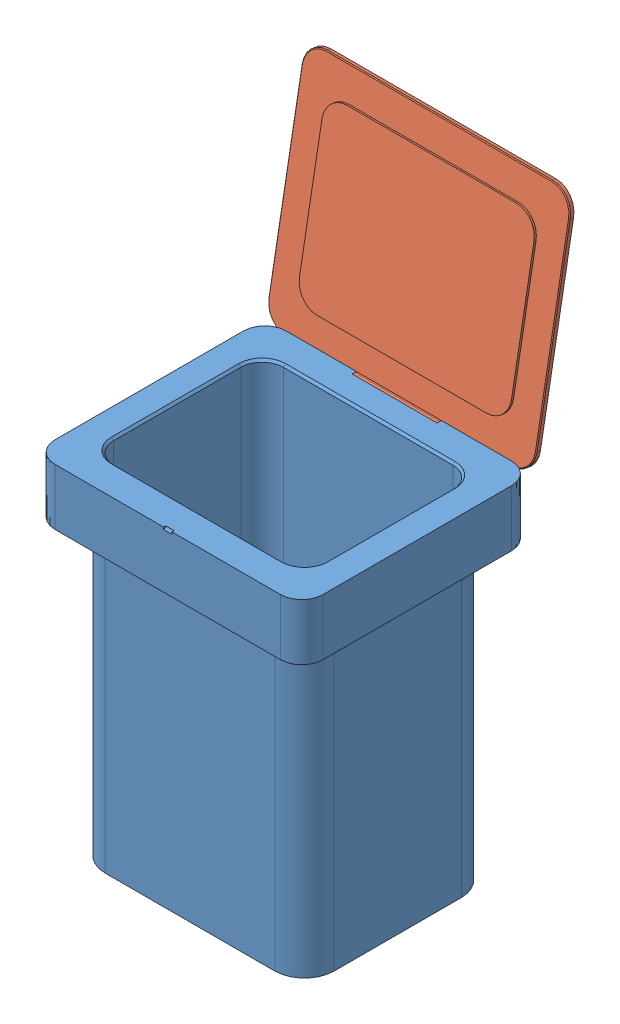
SolidWorks assembly Bin_assembly, configuration Default. Lengths in mm.
Overall size (632 1355.43 649.91).
2 component instances, 2 part files, 2 mates.
Components (placement in the parent):
- bin_bottom-1: bin_bottom [Default] at (512.2775 60.0719 781.0786) size (632 828 545)
- bin_flap-1: bin_flap [Default] at (512.2775 1124.6256 456.606) x (1 0 0) z (0 0.984355 -0.176195) size (632 20 545)
Mates (geometry in assembly coordinates):
- Coincident1: coincident anti-aligned: plane of bin_bottom-1 through (612.2775 863.0719 513.5786) normal (-1 0 0); plane of bin_flap-1 through (612.2775 856.6682 516.5824) normal (1 0 0)
- Concentric1: concentric anti-aligned: cylinder of bin_bottom-1 through (196.2755 863.0719 513.5786) axis (1 0 0) radius 1.9889; cylinder of bin_flap-1 through (828.2785 863.0719 513.5786) axis (-1 0 0) radius 2
